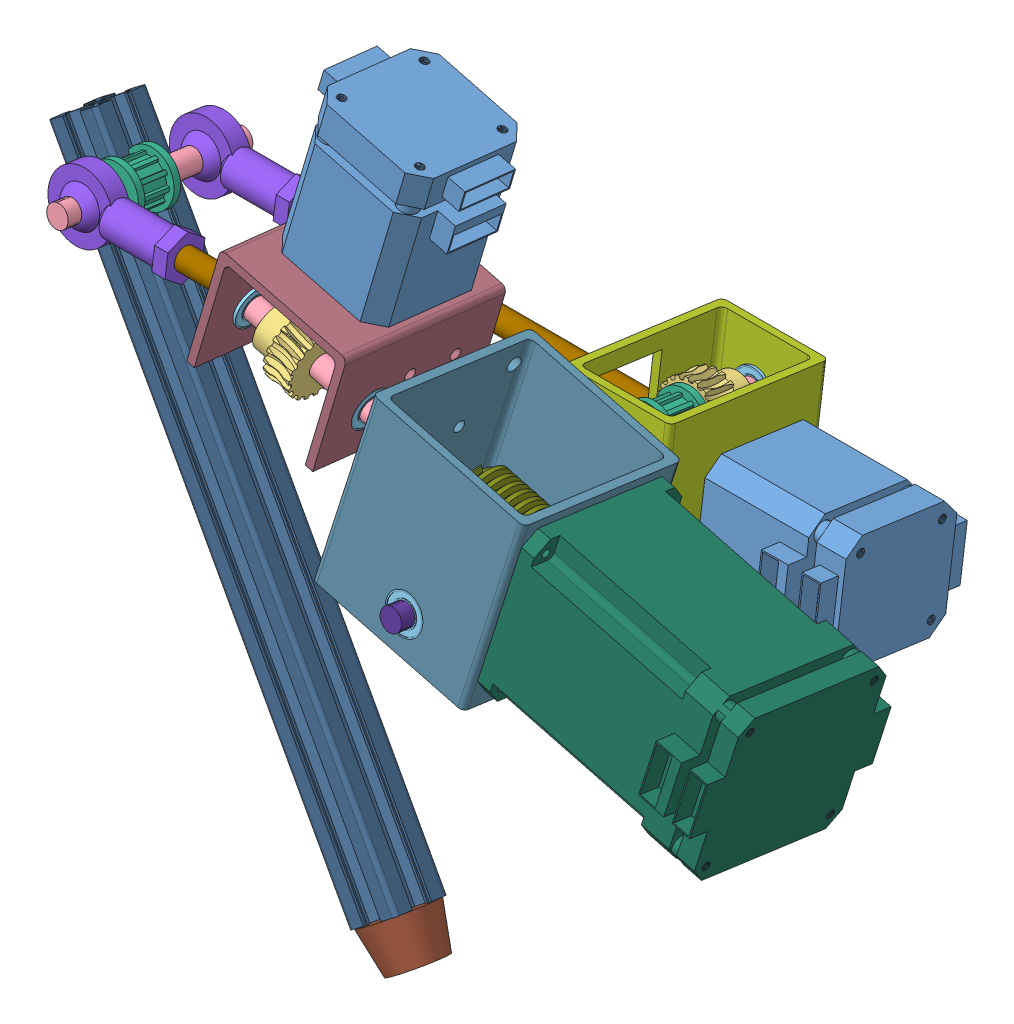
SolidWorks assembly Asm_42Leg, configuration 默认. Lengths in mm.
Overall size (355.64 322.62 152.8).
37 component instances, 17 part files, 24 mates.
Components (placement in the parent):
- Asm_42Driver_90Degree-1: Asm_42Driver_90Degree [默认] at (-49.0062 -2.2844 61.6136) size (98.8 67.62 71.02)
  - Part_42Motor-1: Part_42Motor [默认] at (65.4672 -14.0309 56.4881) x (0 0.990656 -0.136383) z (0 0.136383 0.990656) size (42 76 55.7)
  - Part_Shaft_1Modulus_1Teeth_42SMotor-1: Part_Shaft_1Modulus_1Teeth_42SMotor [默认] at (-21.5328 3.9089 32.8203) x (1 0 0) z (0 0.681581 -0.731743) size (33.1 17.69 17.84)
  - Part_Turbine_1Modulus_20Teeth_42SMotor-1: Part_Turbine_1Modulus_20Teeth_42SMotor [默认] at (-10.5328 22.4226 35.3187) x (0 -0.990656 0.136383) z (1 0 0) size (29.84 18 44.58)
  - Part_Axis_8mm_Turbine_Rocker-1: Part_Axis_8mm_Turbine_Rocker [默认] at (-10.5328 17.922 2.627) x (0.931599 0.360092 -0.049574) z (0 0.136383 0.990656) size (8 17.7 70)
  - Part_Bearing_MR148ZZ-1: Part_Bearing_MR148ZZ [默认] at (-10.5328 19.1494 11.5429) x (0 -0.136383 -0.990656) z (0.425184 0.89665 -0.123441) size (4 14 14)
  - Part_Bearing_MR148ZZ-2: Part_Bearing_MR148ZZ [默认] at (-10.5328 26.7869 67.0197) x (0 -0.136383 -0.990656) z (-0.945462 0.322689 -0.044424) size (4 14 14)
  - Part_SyncWheel_XL10AF_Axis_8mm-2: Part_SyncWheel_XL10AF_Axis_8mm [默认] at (-10.5328 24.2638 48.6925) x (0 -0.136383 -0.990656) z (0.128031 -0.982503 0.13526) size (16 19 19)
  - Part_Flange_42Motor-1: Part_Flange_42Motor [默认] at (-27.5328 -22.013 13.172) x (0 0.990656 -0.136383) z (0 -0.136383 -0.990656) size (60 40 60)
- Asm_Link_Screw_Fisheye-1: Asm_Link_Screw_Fisheye [默认] at (-6.4242 13.7939 -3.2689) size (232.49 25.69 17.14)
  - Part_Fisheye_M8-1: Part_Fisheye_M8 [默认] at (-214.1147 -9.0687 127.5588) x (0 -0.136383 -0.990656) z (0 0.990656 -0.136383) size (14 48.05 24)
  - Part_Screw_M8-1: Part_Screw_M8 [默认] at (-230.1147 -9.0687 127.5588) x (0 -1 0.00007) z (0 0.00007 1) size (8.59 200.96 8.59)
- Asm_Link_Screw_Fisheye-3: Asm_Link_Screw_Fisheye [默认] at (-6.4242 7.5203 -48.8391) size (232.49 25.69 17.14)
  - Part_Fisheye_M8-1: Part_Fisheye_M8 [默认] at (-214.1147 -9.0687 127.5588) x (0 -0.136383 -0.990656) z (0 0.990656 -0.136383) size (14 48.05 24)
  - Part_Screw_M8-1: Part_Screw_M8 [默认] at (-230.1147 -9.0687 127.5588) x (0 -1 0.00007) z (0 0.00007 1) size (8.59 200.96 8.59)
- Part_Axis_8mm_Turbine_Rocker-1: Part_Axis_8mm_Turbine_Rocker [默认] at (-256.5389 -3.1849 66.8319) x (0.902761 0.426123 -0.058664) z (0 0.136383 0.990656) size (8 17.7 70)
- Part_MT2020W-1: Part_MT2020W [默认] at (-146.0416 -173.4388 118.6952) x (0.808736 0.582676 -0.080217) z (0.007956 0.125533 0.992058) size (20 230 20)
- Part_Footpad_M5-1: Part_Footpad_M5 [默认] at (-146.0416 -173.4388 118.6952) x (-0.67041 -0.551002 -0.496938) z (-0.452402 -0.227304 0.862361) size (25 15 25)
- Part_Flange_Axis_8mm_Shoulder-1: Part_Flange_Axis_8mm_Shoulder [默认] at (-56.5389 2.1265 134.742) x (0 0.136383 0.990656) z (-1 0 0) size (13 32 32)
- Asm_42Driver_90Degree_Shoulder-2: Asm_42Driver_90Degree_Shoulder [默认] at (-156.7182 61.3125 151.8525) x (0.217989 0.970746 -0.100662) z (0.967778 -0.228331 -0.106162) size (100.8 66.26 73.14)
  - Part_42Motor-1: Part_42Motor [默认] at (65.4672 -14.0309 56.4881) x (0 0.990656 -0.136383) z (0 0.136383 0.990656) size (42 76 55.7)
  - Part_Shaft_1Modulus_1Teeth_42SMotor-1: Part_Shaft_1Modulus_1Teeth_42SMotor [默认] at (-21.5328 3.9089 32.8203) x (1 0 0) z (0 -0.868578 0.495552) size (33.1 17.69 17.84)
  - Part_Turbine_1Modulus_20Teeth_42SMotor-1: Part_Turbine_1Modulus_20Teeth_42SMotor [默认] at (-12.5328 22.4226 35.3187) x (0 -0.990656 0.136383) z (1 0 0) size (29.84 18 44.58)
  - Part_Axis_8mm_Turbine_Rocker-1: Part_Axis_8mm_Turbine_Rocker [默认] at (-12.5328 18.3311 5.599) x (0.931599 0.360092 -0.049574) z (0 0.136383 0.990656) size (8 17.7 70)
  - Part_Bearing_MR148ZZ-1: Part_Bearing_MR148ZZ [默认] at (-12.5328 18.8767 9.5616) x (0 -0.136383 -0.990656) z (0.425184 0.89665 -0.123441) size (4 14 14)
  - Part_Bearing_MR148ZZ-2: Part_Bearing_MR148ZZ [默认] at (-12.5328 25.1503 55.1318) x (0 -0.136383 -0.990656) z (-0.945462 0.322689 -0.044424) size (4 14 14)
  - Part_Flange_42Motor_Shoulder-1: Part_Flange_42Motor_Shoulder [默认] at (-27.5328 -24.2671 11.4634) x (0 0.990656 -0.136383) z (0 -0.136383 -0.990656) size (60 40 50)
- Asm_57Driver_90Degree_Shoulder-1: Asm_57Driver_90Degree_Shoulder [默认] at (-66.6507 88.0599 152.0881) x (-0.218105 -0.966806 0.133099) z (0 0.136383 0.990656) size (65 146 80)
  - Part_Flange_57Motor_Shoulder-1: Part_Flange_57Motor_Shoulder [默认] at (26.0668 -4.0802 43.0962) size (65 60 60)
  - Part_57Motor-1: Part_57Motor [默认] at (86.0668 141.9198 36.5962) x (-1 0 0) z (0 0 1) size (57 110 69.7)
  - Part_Turbine_1Modulus_20Teeth_42SMotor-1: Part_Turbine_1Modulus_20Teeth_42SMotor [默认] at (78.5668 27.9198 18.0962) x (-1 0 0) z (0 -1 0) size (29.84 18 44.58)
  - Part_Bearing_MR148ZZ-1: Part_Bearing_MR148ZZ [默认] at (78.5668 27.9198 -12.9038) x (0 0 -1) z (0.425184 0.905107 0) size (4 14 14)
  - Part_Bearing_MR148ZZ-2: Part_Bearing_MR148ZZ [默认] at (78.5668 27.9198 43.0962) x (0 0 -1) z (-0.945462 0.325732 0) size (4 14 14)
  - Part_Shaft_1Modulus_4Teeth_57SMotor-1: Part_Shaft_1Modulus_4Teeth_57SMotor [默认] at (57.5668 16.4198 13.0962) x (0 1 0) z (-0.930054 0 0.367423) size (36.16 24.18 24.06)
  - Part_Axis_8mm_Turbine_Shoulder-1: Part_Axis_8mm_Turbine_Shoulder [默认] at (78.5668 27.9198 -31.9038) size (8 17.7 80)
- Part_Flange_Axis_8mm_Shoulder-2: Part_Flange_Axis_8mm_Shoulder [默认] at (-86.3342 34.753 172.6465) x (-0.975925 0.216067 -0.029746) z (0 -0.136383 -0.990656) size (13 32 32)
- Part_SyncWheel_XL10AF_Axis_8mm-1: Part_SyncWheel_XL10AF_Axis_8mm [默认] at (-256.5389 3.1569 112.8974) x (0 -0.136383 -0.990656) z (0.999457 0.032644 -0.004494) size (16 19 19)
Mates (geometry in assembly coordinates):
- 平行3: parallel anti-aligned: plane of Asm_42Driver_90Degree-1/Part_Flange_42Motor-1 through (-39.5389 35.8238 71.5559) normal (-1 0 0); plane of Asm_Link_Screw_Fisheye-1/Part_Fisheye_M8-1 through (-220.5389 4.7253 124.29) normal (1 0 0)
- 平行4: parallel aligned: plane of Asm_42Driver_90Degree-1/Part_SyncWheel_XL20_Axis_8mm-1 through (-59.5389 20.1382 96.9323) normal (0 -0.136383 -0.990656); plane of Asm_Link_Screw_Fisheye-1/Part_Fisheye_M8-1 through (-256.5389 4.265 120.9465) normal (0 -0.136383 -0.990656)
- 同心2: concentric aligned: cylinder of Asm_Link_Screw_Fisheye-1/Part_Fisheye_M8-1 through (-256.5389 5.8078 132.1533) axis (0 -0.136383 -0.990656) radius 4; cylinder of Asm_Link_Screw_Fisheye-3/Part_Fisheye_M8-1 through (-256.5389 -0.4658 86.5831) axis (0 -0.136383 -0.990656) radius 4
- 重合4: coincident aligned: plane of Asm_Link_Screw_Fisheye-1/Part_Screw_M8-1 through (-36.5389 4.7253 124.29) normal (1 0 0); plane of Asm_Link_Screw_Fisheye-3/Part_Screw_M8-1 through (-36.5389 -1.5483 78.7198) normal (1 0 0)
- 同心6: concentric anti-aligned: cylinder of Asm_42Driver_90Degree-1/Part_Flange_42Motor-1 through (-36.5389 4.7253 124.29) axis (1 0 0) radius 3.4; cylinder of Asm_Link_Screw_Fisheye-1/Part_Screw_M8-1 through (-36.5389 4.7253 124.29) axis (-1 0 0) radius 4
- 重合7: coincident aligned: plane of Asm_42Driver_90Degree-1/Part_Flange_42Motor-1 through (-36.5389 43.0521 124.0607) normal (1 0 0); plane of Asm_Link_Screw_Fisheye-1/Part_Screw_M8-1 through (-36.5389 4.7253 124.29) normal (1 0 0)
- 距离2: distance = 8.625 mm aligned: plane of Part_Axis_8mm_Turbine_Rocker-1 through (-256.5389 6.3619 136.1778) normal (0 0.136383 0.990656); plane of Asm_Link_Screw_Fisheye-1/Part_Fisheye_M8-1 through (-256.5389 5.1856 127.6334) normal (0 0.136383 0.990656)
- 同心7: concentric anti-aligned: cylinder of Asm_Link_Screw_Fisheye-3/Part_Screw_M8-1 through (-36.5389 -1.5483 78.7198) axis (-1 0 0) radius 4; cylinder of Asm_42Driver_90Degree-1/Part_Flange_42Motor-1 through (-36.5389 -1.5483 78.7198) axis (1 0 0) radius 3.4
- 同心9: concentric anti-aligned: cylinder of Part_MT2020W-1 through (-281.3088 11.2399 96.4112) axis (0.588118 -0.802951 0.096887) radius 2.5; cylinder of Part_Footpad_M5-1 through (-146.0416 -173.4388 118.6952) axis (-0.588118 0.802951 -0.096887) radius 5
- 重合14: coincident anti-aligned: plane of Part_MT2020W-1 through (-146.0416 -173.4388 118.6952) normal (0.588118 -0.802951 0.096887); plane of Part_Footpad_M5-1 through (-137.6615 -166.5513 124.907) normal (-0.588118 0.802951 -0.096887)
- 重合18: coincident anti-aligned: plane of Asm_42Driver_90Degree-1/Part_Flange_42Motor-1 through (-74.5389 43.3249 126.042) normal (0 0.136383 0.990656); plane of Part_Flange_Axis_8mm_Shoulder-1 through (-56.5389 1.7173 131.7701) normal (0 -0.136383 -0.990656)
- 同心16: concentric aligned: cylinder of Asm_42Driver_90Degree-1/Part_Flange_42Motor-1 through (-48.0536 -14.8718 73.487) axis (0 0.136383 0.990656) radius 2; cylinder of Part_Flange_Axis_8mm_Shoulder-1 through (-48.0536 -6.6888 132.9263) axis (0 0.136383 0.990656) radius 2
- 同心20: concentric aligned: cylinder of Asm_42Driver_90Degree-1/Part_Flange_42Motor-1 through (-65.0242 1.9402 71.1725) axis (0 0.136383 0.990656) radius 2; cylinder of Part_Flange_Axis_8mm_Shoulder-1 through (-65.0242 10.1232 130.6118) axis (0 0.136383 0.990656) radius 2
- 同心25: concentric aligned: cylinder of Part_Flange_Axis_8mm_Shoulder-1 through (-56.5389 3.4903 144.6486) axis (0 -0.136383 -0.990656) radius 4; cylinder of Asm_57Driver_90Degree_Shoulder-1/Part_Axis_8mm_Turbine_Shoulder-1 through (-56.5389 12.628 211.0226) axis (0 -0.136383 -0.990656) radius 4
- 重合24: coincident anti-aligned: plane of Asm_42Driver_90Degree-1/Part_Flange_42Motor-1 through (-74.5389 43.3249 126.042) normal (0 0.136383 0.990656); plane of Asm_57Driver_90Degree_Shoulder-1/Part_Axis_8mm_Turbine_Shoulder-1 through (-56.5389 1.7173 131.7701) normal (0 -0.136383 -0.990656)
- 重合26: coincident anti-aligned: plane of Asm_57Driver_90Degree_Shoulder-1/Part_Flange_57Motor_Shoulder-1 through (-90.4948 -1.1351 149.3231) normal (-0.975925 0.216067 -0.029746); plane of Part_Flange_Axis_8mm_Shoulder-2 through (-83.4064 34.1048 172.7358) normal (0.975925 -0.216067 0.029746)
- 同心26: concentric aligned: cylinder of Asm_57Driver_90Degree_Shoulder-1/Part_Flange_57Motor_Shoulder-1 through (-22.9993 30.5015 181.7971) axis (-0.975925 0.216067 -0.029746) radius 2; cylinder of Part_Flange_Axis_8mm_Shoulder-2 through (-81.5548 43.4655 180.0124) axis (-0.975925 0.216067 -0.029746) radius 2
- 同心27: concentric aligned: cylinder of Asm_57Driver_90Degree_Shoulder-1/Part_Flange_57Motor_Shoulder-1 through (-22.9993 28.187 164.9851) axis (-0.975925 0.216067 -0.029746) radius 2; cylinder of Part_Flange_Axis_8mm_Shoulder-2 through (-81.5548 41.151 163.2004) axis (-0.975925 0.216067 -0.029746) radius 2
- 同心28: concentric anti-aligned: cylinder of Asm_42Driver_90Degree_Shoulder-2/Part_Axis_8mm_Turbine_Rocker-1 through (-83.4064 34.1048 172.7358) axis (-0.975925 0.216067 -0.029746) radius 4; cylinder of Part_Flange_Axis_8mm_Shoulder-2 through (-96.0935 36.9137 172.3491) axis (0.975925 -0.216067 0.029746) radius 4
- 重合27: coincident anti-aligned: plane of Asm_42Driver_90Degree_Shoulder-2/Part_Axis_8mm_Turbine_Rocker-1 through (-83.4064 34.1048 172.7358) normal (0.975925 -0.216067 0.029746); plane of Asm_57Driver_90Degree_Shoulder-1/Part_Flange_57Motor_Shoulder-1 through (-90.4948 -1.1351 149.3231) normal (-0.975925 0.216067 -0.029746)
- 同心29: concentric anti-aligned: cylinder of Part_Axis_8mm_Turbine_Rocker-1 through (-256.5389 6.3619 136.1778) axis (0 -0.136383 -0.990656) radius 4; cylinder of Part_SyncWheel_XL10AF_Axis_8mm-1 through (-256.5389 1.6567 102.0002) axis (0 0.136383 0.990656) radius 4
- 同心30: concentric aligned: cylinder of Asm_Link_Screw_Fisheye-1/Part_Fisheye_M8-1 through (-256.5389 5.8078 132.1533) axis (0 -0.136383 -0.990656) radius 4; cylinder of Part_Axis_8mm_Turbine_Rocker-1 through (-256.5389 6.3619 136.1778) axis (0 -0.136383 -0.990656) radius 4
- 重合29: coincident aligned: plane of Asm_42Driver_90Degree-1/Part_SyncWheel_XL10AF_Axis_8mm-2 through (-59.5389 22.3203 112.7828) normal (0 0.136383 0.990656); plane of Part_SyncWheel_XL10AF_Axis_8mm-1 through (-256.5389 3.4978 115.374) normal (0 0.136383 0.990656)
- 相切1: tangent anti-aligned: cylinder of Part_Axis_8mm_Turbine_Rocker-1 through (-256.5389 6.3619 136.1778) axis (0 -0.136383 -0.990656) radius 4; plane of Part_MT2020W-1 through (-273.301 15.8113 85.6884) normal (0.808736 0.582676 -0.080217)
